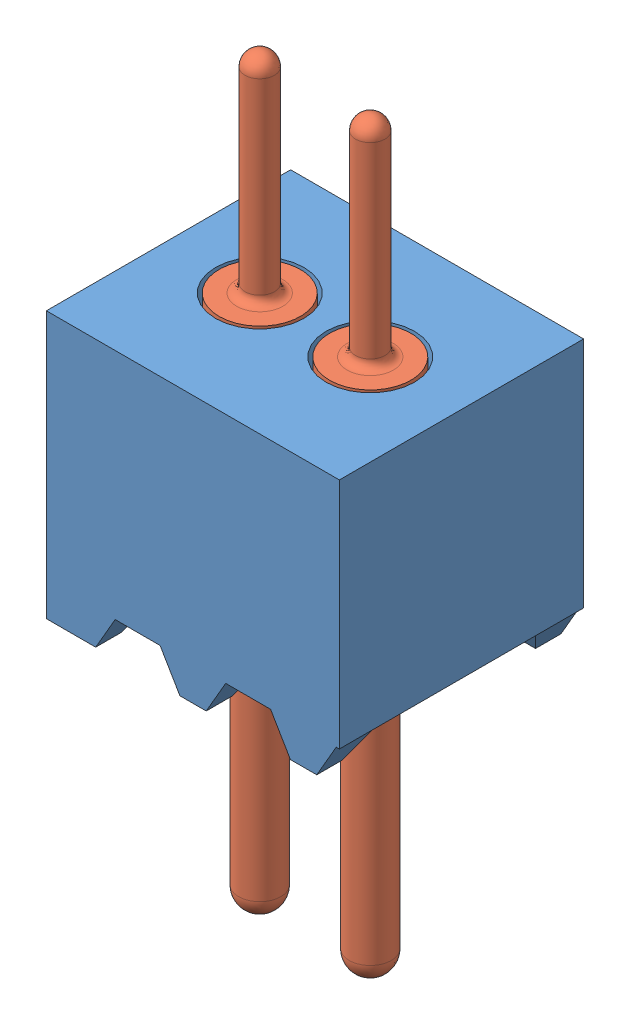
SolidWorks assembly mill-max-860-10-002-10-002000, configuration Default. Lengths in mm.
Overall size (2.65 6.73 2.21).
3 component instances, 2 part files, 0 mates.
Components (placement in the parent):
- mill-max-860-10-002-10-002000_P8XX-18-015-05-000000(P802-18-015-05-000000)-1: mill-max-860-10-002-10-002000_P8XX-18-015-05-000000(P802-18-015-05-000000) [Default] at origin size (2.65 2.41 2.21)
- mill-max-860-10-002-10-002000_3039-1: mill-max-860-10-002-10-002000_3039 [Default] at (0.8255 1.905 -1.1049) x (0 -1 0) z (0 0 1) size (6.73 0.74 0.74)
- mill-max-860-10-002-10-002000_3039-2: mill-max-860-10-002-10-002000_3039 [Default] at (1.8255 1.905 -1.1049) x (0 -1 0) z (0 0 1) size (6.73 0.74 0.74)
